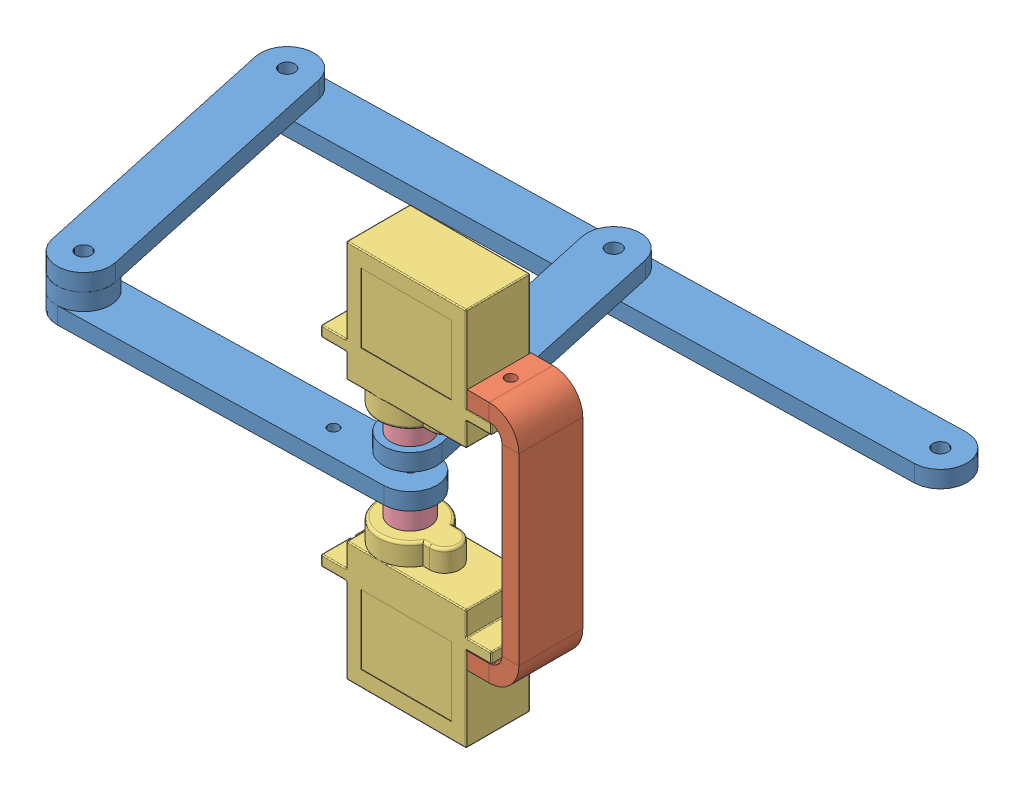
SolidWorks assembly ArmsAssem, configuration Default. Lengths in mm.
Overall size (131.03 71.31 63.4).
10 component instances, 4 part files, 28 mates.
Components (placement in the parent):
- Arms-1: Arms [120mmLong] at (-27.1104 34.0723 -54.8612) x (-0.999733 0 0.023094) z (-0.023094 0 -0.999733) size (130 3.17 10)
- Arms-2: Arms [60mmLong] at (-46.492 34.0673 -5.3072) x (-0.999733 0 0.023094) z (0.023094 0 0.999733) size (70 3.17 10)
- Arms-3: Arms [40mmInside] at (-21.8052 37.2473 -30.4306) x (-0.212209 0 -0.977224) z (0.977224 0 -0.212209) size (60 3.17 10)
- Arms-4: Arms [40mmOutside] at (-81.7892 37.2473 -29.045) x (0.212209 0 0.977224) z (-0.977224 0 0.212209) size (60 3.17 10)
- TempClamp-1: TempClamp [Default] at (6.745 35.655 -6) x (-1 0 0) z (0 1 0) size (9.73 12 45.67)
- Micro Servo FS90R Continuous-1: Micro Servo FS90R Continuous [Valor predeterminado] at (-11.25 55.3146 -6) x (1 0 0) z (0 0 -1) size (32 29 12)
- Micro Servo Horn Single Arm-3: Micro Servo Horn Single Arm [Default] at (-16.5 42.0352 -6) x (0.312823 0 0.949811) z (0.949811 0 -0.312823) size (19.74 4.23 7.24)
- Micro Servo FS90R Continuous-2: Micro Servo FS90R Continuous [Valor predeterminado] at (-11.25 16 -6) size (32 29 12)
- Micro Servo Horn Single Arm-4: Micro Servo Horn Single Arm [Default] at (-16.5 29.2794 -6) x (0.999445 0 -0.033323) z (0.033323 0 0.999445) size (19.74 4.23 7.24)
- Arms-5: Arms [Spacer] at (-76.484 34.0673 -4.6144) x (-0.904728 0 -0.42599) z (0.42599 0 -0.904728) size (10 3.18 10)
Mates (geometry in assembly coordinates):
- Coincident61: coincident anti-aligned: plane of Micro Servo FS90R Continuous-2 through (-16.5 29 -6) normal (0 1 0); plane of Micro Servo Horn Single Arm-4 through (-16.5 29 -6) normal (0 -1 0)
- Coincident62: coincident anti-aligned: plane of Micro Servo FS90R Continuous-1 through (-16.5 42.3146 -6) normal (0 -1 0); plane of Micro Servo Horn Single Arm-3 through (-16.5 42.3146 -6) normal (0 1 0)
- Coincident76: coincident aligned: plane of Micro Servo FS90R Continuous-2 through (-22.5 0 0) normal (0 0 1)
- Coincident69: coincident aligned: plane of Micro Servo FS90R Continuous-2 through (0 0 -12) normal (1 0 0)
- Coincident70: coincident anti-aligned: plane of Arms-2 through (-76.484 30.8923 -4.6144) normal (0 -1 0); plane of Micro Servo Horn Single Arm-4 through (-16.5 30.8923 -6) normal (0 1 0)
- Coincident66: coincident anti-aligned: plane of Micro Servo FS90R Continuous-2 through (-11.25 0 -6) normal (0 -1 0)
- Coincident71: coincident anti-aligned: plane of Arms-3 through (-27.1104 40.4223 -54.8612) normal (0 1 0); plane of Micro Servo Horn Single Arm-3 through (-16.5 40.4223 -6) normal (0 -1 0)
- Coincident78: coincident aligned: plane of Micro Servo FS90R Continuous-2 through (0 0 -12) normal (1 0 0)
- Coincident77: coincident aligned: plane of Micro Servo FS90R Continuous-1 through (0 71.3146 0) normal (1 0 0); plane of Micro Servo FS90R Continuous-2 through (0 0 -12) normal (1 0 0)
- Coincident79: coincident aligned: plane of Micro Servo FS90R Continuous-1 through (-22.5 71.3146 0) normal (0 0 1); plane of Micro Servo FS90R Continuous-2 through (-22.5 0 0) normal (0 0 1)
- Coincident80: coincident aligned: plane of Micro Servo FS90R Continuous-1 through (0 71.3146 0) normal (1 0 0); plane of Micro Servo FS90R Continuous-2 through (0 0 -12) normal (1 0 0)
- Coincident72: coincident anti-aligned: plane of Arms-2 through (-76.484 34.0673 -4.6144) normal (0 1 0); plane of Arms-5 through (-76.484 34.0673 -4.6144) normal (0 -1 0)
- Coincident73: coincident anti-aligned: plane of Arms-4 through (-76.484 37.2473 -4.6144) normal (0 -1 0); plane of Arms-5 through (-76.484 37.2473 -4.6144) normal (0 1 0)
- Coincident74: coincident anti-aligned: plane of Arms-1 through (-87.0944 37.2473 -53.4756) normal (0 1 0); plane of Arms-4 through (-76.484 37.2473 -4.6144) normal (0 -1 0)
- Coincident75: coincident anti-aligned: plane of Arms-1 through (-87.0944 37.2473 -53.4756) normal (0 1 0); plane of Arms-3 through (-27.1104 37.2473 -54.8612) normal (0 -1 0)
- Concentric58: concentric aligned: cylinder of Micro Servo FS90R Continuous-2 through (-16.5 29 -6) axis (0 -1 0) radius 2.25; cylinder of Micro Servo Horn Single Arm-4 through (-16.5 29 -6) axis (0 -1 0) radius 2.286
- Concentric59: concentric aligned: cylinder of Micro Servo FS90R Continuous-1 through (-16.5 42.3146 -6) axis (0 1 0) radius 2.25; cylinder of Micro Servo Horn Single Arm-3 through (-16.5 42.3146 -6) axis (0 1 0) radius 2.286
- Concentric64: concentric aligned: cylinder of Arms-3 through (-16.5 40.4223 -6) axis (0 -1 0) radius 0.75; cylinder of Micro Servo FS90R Continuous-1 through (-16.5 47.3146 -6) axis (0 -1 0) radius 0.75
- Concentric65: concentric aligned: cylinder of Arms-2 through (-16.5 30.8923 -6) axis (0 1 0) radius 0.75; cylinder of Micro Servo FS90R Continuous-2 through (-16.5 24 -6) axis (0 1 0) radius 0.75
- Concentric66: concentric aligned: cylinder of Arms-2 through (-16.5 30.8923 -6) axis (0 1 0) radius 0.75; cylinder of Micro Servo FS90R Continuous-2 through (-16.5 24 -6) axis (0 1 0) radius 0.75
- Concentric70: concentric aligned: cylinder of Arms-3 through (-16.5 40.4223 -6) axis (0 -1 0) radius 0.75; cylinder of Micro Servo FS90R Continuous-1 through (-16.5 47.3146 -6) axis (0 -1 0) radius 0.75
- Concentric71: concentric anti-aligned: cylinder of Arms-2 through (-76.484 30.8923 -4.6144) axis (0 1 0) radius 1.42; cylinder of Arms-5 through (-76.484 37.2473 -4.6144) axis (0 -1 0) radius 1.42
- Concentric72: concentric aligned: cylinder of Arms-4 through (-76.484 40.4223 -4.6144) axis (0 -1 0) radius 1.42; cylinder of Arms-5 through (-76.484 37.2473 -4.6144) axis (0 -1 0) radius 1.42
- Concentric73: concentric aligned: cylinder of Arms-1 through (-87.0944 37.2473 -53.4756) axis (0 -1 0) radius 1.42; cylinder of Arms-4 through (-87.0944 40.4223 -53.4756) axis (0 -1 0) radius 1.42
- Concentric74: concentric anti-aligned: cylinder of Arms-1 through (-27.1104 34.0723 -54.8612) axis (0 1 0) radius 1.42; cylinder of Arms-3 through (-27.1104 40.4223 -54.8612) axis (0 -1 0) radius 1.42
- Coincident81: coincident: plane of TempClamp-1 through (0.195 16 0) normal (0 1 0); plane of Micro Servo FS90R Continuous-2 through (2.375 16 -6) normal (0 -1 0)
- Concentric75: concentric: cylinder of TempClamp-1 through (2.375 12.82 -6) axis (0 1 0) radius 1; cylinder of Micro Servo FS90R Continuous-2 through (2.375 18 -6) axis (0 -1 0) radius 1
- Parallel1: parallel anti-aligned: plane of TempClamp-1 through (0.195 12.82 0) normal (-1 0 0); plane of Micro Servo FS90R Continuous-2 through (0 0 -12) normal (1 0 0)
